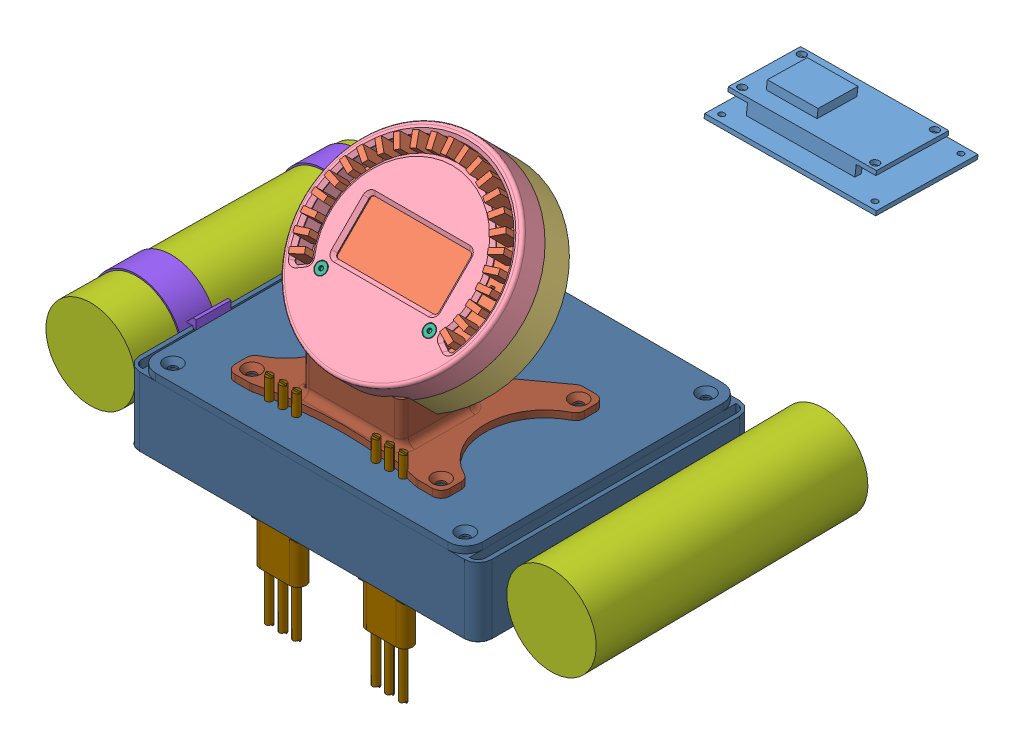
SolidWorks assembly ElectronicsHousing, configuration Default. Lengths in mm.
Overall size (203.55 146.57 210.62).
16 component instances, 11 part files, 31 mates.
Components (placement in the parent):
- ESP32-1: ESP32 [Default] at (7.8983 33.4646 -183.2036) x (-0.059205 -0.078016 -0.995193) z (-0.997373 0.046308 0.055705) size (40.13 13.03 60.2)
- DRO_Housing_Assembly-1: DRO_Housing_Assembly [Default] at (0 42.7411 -46.8842) x (1 0 0) z (0 -0.707107 0.707107) size (73.19 26.95 73.19)
  - DRO_PCB-1: DRO_PCB [Default] at (0 12.7 0) x (1 0 0) z (0 1 0) size (70.54 70.54 16.8)
  - DRO_Housing-1: DRO_Housing [Default] at (0 0 -0.0001) size (73.19 12.7 73.19)
  - DRO_Housing_Top-1: DRO_Housing_Top [Default] at (0 22.6058 -0.0001) size (73.19 11.51 73.19)
  - 94180A307_HEAT-SET INSERTS FOR PLASTICS-1: 94180A307_HEAT-SET INSERTS FOR PLASTICS [Default] at (-20 12.7 13.82) x (0.986698 0 0.162567) z (-0.162567 0 0.986698) size (3.58 3.11 3.58)
  - 94180A307_HEAT-SET INSERTS FOR PLASTICS-2: 94180A307_HEAT-SET INSERTS FOR PLASTICS [Default] at (20 12.7 13.82) x (0.986698 0 0.162567) z (-0.162567 0 0.986698) size (3.58 3.11 3.58)
  - 91294A539_BLACK ALLOY STEEL FLAT-HEAD SOCKET CAP SCREW-1: 91294A539_BLACK ALLOY STEEL FLAT-HEAD SOCKET CAP SCREW [91294A539] at (-20 24.2058 13.82) x (0.968702 0 -0.248226) z (0 1 0) size (4 4 20.3)
  - 91294A539_BLACK ALLOY STEEL FLAT-HEAD SOCKET CAP SCREW-2: 91294A539_BLACK ALLOY STEEL FLAT-HEAD SOCKET CAP SCREW [91294A539] at (20 24.2058 13.82) x (0.968702 0 -0.248226) z (0 1 0) size (4 4 20.3)
- HandelBars-1: HandelBars [Default] at origin size (203.2 33.02 101.6)
- HandleBarsMount-1: HandleBarsMount [Top] at (-84.7192 0 -29.661) x (0.999922 0 0.012499) z (0 -1 0) size (39.16 12.7 34.15)
- 9552T610_Molex_Connector-1: 9552T610_Molex_Connector [9552T61] at (19.7083 -23.0072 -5.6199) x (1 0 0) z (0 -1 0) size (19.56 8.64 80)
- ESP32_Housing-1: ESP32_Housing [Default] at (0 -14.8854 -43.7199) size (130.2 27.94 101.6)
- 9552T610_Molex_Connector-2: 9552T610_Molex_Connector [9552T61] at (-19.7083 -23.0072 -5.6199) x (1 0 0) z (0 -1 0) size (19.56 8.64 80)
- HandleBarsMount-4: HandleBarsMount [Top] at (-83.8666 0 -97.8752) x (0.999922 0 0.012499) z (0 -1 0) size (39.16 12.7 34.15)
- DRO_Pedestal-1: DRO_Pedestal [Default] at (0 13.0546 -34.8299) size (79.38 17.78 60.32)
Mates (geometry in assembly coordinates):
- Coincident1: coincident aligned: plane of HandelBars-1 through (0 0 0) normal (0 1 0)
- Coincident2: coincident aligned: plane of HandelBars-1 through (0 0 0) normal (1 0 0)
- Coincident3: coincident aligned: plane of HandelBars-1 through (0 0 0) normal (0 0 1)
- Coincident14: coincident aligned: plane of DRO_Housing_Assembly-1 through (0 42.7411 -46.8842) normal (1 0 0)
- Concentric12: concentric aligned: circle of HandelBars-1; circle of HandleBarsMount-2
- Parallel4: parallel anti-aligned: plane of HandleBarsMount-2 through (-61.976 -6.35 -0.3525) normal (0 -1 0)
- Coincident16: coincident anti-aligned: plane of 9552T610_Molex_Connector-1 through (11.1993 -13.6854 -8.6679) normal (0 -1 0); plane of ESP32_Housing-1 through (53.975 -13.6854 -88.1699) normal (0 1 0)
- Coincident17: coincident aligned: plane of 9552T610_Molex_Connector-1 through (19.7083 -23.0072 -5.6199) normal (1 0 0); plane of ESP32_Housing-1 through (19.7083 -14.8854 -43.7199) normal (1 0 0)
- Coincident18: coincident aligned: plane of 9552T610_Molex_Connector-1 through (19.7083 -23.0072 -5.6199) normal (0 0 1); plane of ESP32_Housing-1 through (0 -14.8854 -5.6199) normal (0 0 1)
- Coincident19: coincident anti-aligned: plane of ESP32_Housing-1 through (53.975 -13.6854 -88.1699) normal (0 1 0); plane of 9552T610_Molex_Connector-2 through (-28.2173 -13.6854 -8.6679) normal (0 -1 0)
- Coincident20: coincident aligned: plane of ESP32_Housing-1 through (0 -14.8854 -5.6199) normal (0 0 1); plane of 9552T610_Molex_Connector-2 through (-19.7083 -23.0072 -5.6199) normal (0 0 1)
- Coincident21: coincident aligned: plane of ESP32_Housing-1 through (-19.7083 -14.8854 -43.7199) normal (1 0 0); plane of 9552T610_Molex_Connector-2 through (-19.7083 -23.0072 -5.6199) normal (1 0 0)
- Parallel5: parallel anti-aligned: plane of ESP32_Housing-1 through (53.975 -14.8854 -88.1699) normal (0 -1 0)
- Coincident24: coincident aligned: plane of ESP32_Housing-1 through (0 -14.8854 -43.7199) normal (1 0 0)
- Concentric13: concentric anti-aligned: circle of HandelBars-1; circle of HandleBarsMount-3
- Coincident27: coincident aligned: plane of HandelBars-1 through (-83.82 0 -101.6) normal (0 0 -1); plane of HandleBarsMount-3 through (-83.82 0 -101.6) normal (0 0 -1)
- Parallel6: parallel anti-aligned: plane of HandleBarsMount-1 through (-84.7192 0 -29.661) normal (0 -1 0)
- Parallel7: parallel anti-aligned: plane of HandleBarsMount-3 through (-83.82 0 -101.6) normal (0 -1 0)
- Coincident30: coincident anti-aligned: plane of ESP32_Housing-1 through (53.975 -14.8854 -88.1699) normal (0 -1 0); plane of HandleBarsMount-3 through (-62.935 -14.8854 -76.2) normal (0 1 0)
- Coincident32: coincident anti-aligned: line of HandelBars-1 through (-83.82 0 -101.6) axis (-0.012499 0 0.999922); axis of HandleBarsMount-1 through (-84.878 0 -16.962) axis (0.012499 0 -0.999922)
- Coincident33: coincident anti-aligned: line of HandelBars-1 through (-83.82 0 -101.6) axis (-0.012499 0 0.999922); line of HandleBarsMount-4 through (-84.0253 0 -85.1762) axis (0.012499 0 -0.999922)
- Parallel9: parallel anti-aligned: plane of HandleBarsMount-4 through (-83.8666 0 -97.8752) normal (0 -1 0)
- Concentric14: concentric aligned: cylinder of ESP32_Housing-1 through (-34.925 -14.8854 -60.2299) axis (0 1 0) radius 2.0193; cylinder of DRO_Pedestal-1 through (-34.925 15.5946 -60.2299) axis (0 1 0) radius 1.632
- Concentric15: concentric aligned: cylinder of ESP32_Housing-1 through (-34.925 -14.8854 -9.4299) axis (0 1 0) radius 2.0193; cylinder of DRO_Pedestal-1 through (-34.925 15.5946 -9.4299) axis (0 1 0) radius 1.632
- Concentric16: concentric aligned: cylinder of ESP32_Housing-1 through (34.925 -14.8854 -9.4299) axis (0 1 0) radius 2.0193; cylinder of DRO_Pedestal-1 through (34.925 15.5946 -9.4299) axis (0 1 0) radius 1.632
- Concentric17: concentric aligned: cylinder of ESP32_Housing-1 through (34.925 -14.8854 -60.2299) axis (0 1 0) radius 2.0193; cylinder of DRO_Pedestal-1 through (34.925 15.5946 -60.2299) axis (0 1 0) radius 1.632
- Coincident35: coincident anti-aligned: plane of DRO_Housing_Assembly-1/DRO_Housing-1 through (0 42.7412 -46.8843) normal (0 -0.707107 -0.707107); plane of DRO_Pedestal-1 through (0 16.8646 -21.0077) normal (0 0.707107 0.707107)
- Coincident36: coincident anti-aligned: plane of ESP32_Housing-1 through (53.975 13.0546 -88.1699) normal (0 1 0); plane of DRO_Pedestal-1 through (-36.5125 13.0546 -7.8424) normal (0 -1 0)
- Distance1: distance = 43.7199 mm aligned: plane of ESP32_Housing-1 through (0 -14.8854 -43.7199) normal (0 0 1)
- Concentric18: concentric aligned: cylinder of DRO_Housing_Assembly-1/DRO_Housing-1 through (0 44.5372 -45.0883) axis (0 -0.707107 -0.707107) radius 36.5949; cylinder of DRO_Pedestal-1 through (0 42.7412 -46.8843) axis (0 -0.707107 -0.707107) radius 36.5951
- Coincident37: coincident anti-aligned: plane of HandleBarsMount-1 through (-63.9946 -14.8854 -16.701) normal (0 1 0); plane of ESP32_Housing-1 through (53.975 -14.8854 -88.1699) normal (0 -1 0)
